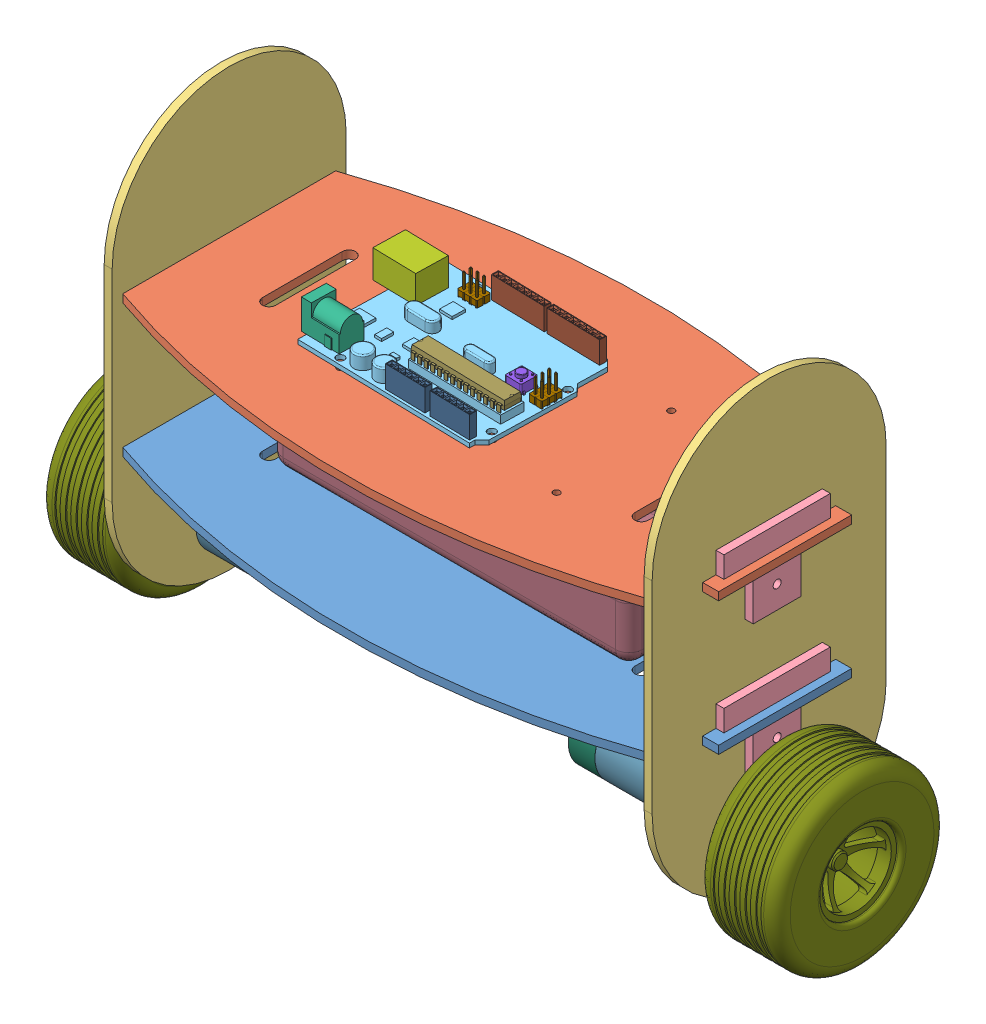
SolidWorks assembly Final Acrylic full robot, configuration Default. Lengths in mm.
Overall size (277.52 186.45 164.77).
33 component instances, 16 part files, 28 mates.
Components (placement in the parent):
- Final Acrylic body-1: Final Acrylic body [Default] at (135.5659 139.3996 253.2306) size (218 3 114.31)
- Final Acrylic body arduino-1: Final Acrylic body arduino [Default] at (135.5659 189.3996 253.2306) size (218 3 164.77)
- Acrylic side-1: Acrylic side [Default] at (235.5659 202.3996 253.2306) size (3 164 88)
- Acrylic side-2: Acrylic side [Default] at (32.5659 202.3996 253.2306) size (3 164 88)
- Acrylic T sec-1: Acrylic T sec [Default] at (241.5659 142.3996 253.2306) x (0 0 1) z (-1 0 0) size (40 28 3)
- Acrylic T sec-2: Acrylic T sec [Default] at (241.5659 192.3996 253.2306) x (0 0 1) z (-1 0 0) size (40 28 3)
- Acrylic T sec-3: Acrylic T sec [Default] at (32.5659 192.3996 253.2306) x (0 0 1) z (-1 0 0) size (40 28 3)
- Acrylic T sec-4: Acrylic T sec [Default] at (32.5659 142.3996 253.2306) x (0 0 1) z (-1 0 0) size (40 28 3)
- User Library-Arduino-UNO-1: User Library-Arduino-UNO [Predeterminado] at (128.4174 198.4807 252.7313) x (0.999721 0 0.023599) z (-0.023599 0 0.999721) size (74.65 14.9 53.3)
  - User Library-Arduino-UNO_Arduino_UNO_PCB-1: User Library-Arduino-UNO_Arduino_UNO_PCB [Predeterminado] at (-41.2845 -4.4325 26.65) size (68.65 6.6 53.3)
  - User Library-Arduino-UNO_User Library-Arduino Mega_DC POWER JACK-1: User Library-Arduino-UNO_User Library-Arduino Mega_DC POWER JACK [Default] at (-43.2845 -2.8325 18.828) x (0 0 1) z (-1 0 0) size (9.47 14.78 14.48)
  - User Library-Arduino-UNO_User Library-Arduino Mega_USB SM host-1: User Library-Arduino-UNO_User Library-Arduino Mega_USB SM host [Default] at (-39.0345 2.4175 -12.65) x (0 0 1) z (-1 0 0) size (14.86 14.22 16.5)
  - User Library-Arduino-UNO_User Library-Arduino Mega_tactile BUTTON-1: User Library-Arduino-UNO_User Library-Arduino Mega_tactile BUTTON [Default] at (15.2655 -2.8325 -1.55) x (1 0 0) z (0 1 0) size (7.9 6.2 7.35)
  - User Library-Arduino-UNO_User Library-Arduino Mega_Header Vertical 2_54mm Pitch4-1-3: User Library-Arduino-UNO_User Library-Arduino Mega_Header Vertical 2_54mm Pitch4-1 [2 Way] at (-21.2045 -2.8325 -20.11) size (2.54 9.3 5.08)
  - User Library-Arduino-UNO_User Library-Arduino Mega_Header Vertical 2_54mm Pitch4-1-4: User Library-Arduino-UNO_User Library-Arduino Mega_Header Vertical 2_54mm Pitch4-1 [2 Way] at (-23.7445 -2.8325 -20.11) size (2.54 9.3 5.08)
  - User Library-Arduino-UNO_User Library-Arduino Mega_Header Vertical 2_54mm Pitch4-1-5: User Library-Arduino-UNO_User Library-Arduino Mega_Header Vertical 2_54mm Pitch4-1 [2 Way] at (-26.2845 -2.8325 -20.11) size (2.54 9.3 5.08)
  - User Library-Arduino-UNO_User Library-Arduino Mega_Header Vertical 2_54mm Pitch4-1-6: User Library-Arduino-UNO_User Library-Arduino Mega_Header Vertical 2_54mm Pitch4-1 [2 Way] at (24.3255 -2.8325 -3.11) x (0 0 -1) z (1 0 0) size (2.54 9.3 5.08)
  - User Library-Arduino-UNO_User Library-Arduino Mega_Header Vertical 2_54mm Pitch4-1-7: User Library-Arduino-UNO_User Library-Arduino Mega_Header Vertical 2_54mm Pitch4-1 [2 Way] at (24.3255 -2.8325 1.97) x (0 0 -1) z (1 0 0) size (2.54 9.3 5.08)
  - User Library-Arduino-UNO_User Library-Arduino Mega_Header Vertical 2_54mm Pitch4-1-8: User Library-Arduino-UNO_User Library-Arduino Mega_Header Vertical 2_54mm Pitch4-1 [2 Way] at (24.3255 -2.8325 -0.57) x (0 0 -1) z (1 0 0) size (2.54 9.3 5.08)
  - User Library-Arduino-UNO_User Library-Arduino Mega_PIN HEADER FEMALE 6-1: User Library-Arduino-UNO_User Library-Arduino Mega_PIN HEADER FEMALE 6 [Default] at (-7.3445 -2.8325 24.38) size (15.24 8.3 2.54)
  - User Library-Arduino-UNO_User Library-Arduino Mega_PIN HEADER FEMALE 6-2: User Library-Arduino-UNO_User Library-Arduino Mega_PIN HEADER FEMALE 6 [Default] at (9.8955 -2.8325 24.38) size (15.24 8.3 2.54)
  - User Library-Arduino-UNO_User Library-Arduino Mega_PIN HEADER FEMALE 8-1: User Library-Arduino-UNO_User Library-Arduino Mega_PIN HEADER FEMALE 8 [Default] at (-17.5745 -2.8325 -24.38) size (20.32 8.3 2.54)
  - User Library-Arduino-UNO_User Library-Arduino Mega_PIN HEADER FEMALE 8-2: User Library-Arduino-UNO_User Library-Arduino Mega_PIN HEADER FEMALE 8 [Default] at (3.7455 -2.8325 -24.38) size (20.32 8.3 2.54)
  - User Library-Arduino-UNO_User Library-28 pin dip-1: User Library-Arduino-UNO_User Library-28 pin dip [Default] at (1.315 2.5165 10.213) x (0 0 -1) z (1 0 0) size (7.87 6.22 35.94)
- Battery-1: Battery [Default] at (69.0496 142.3996 271.4424) x (1 0 0) z (0 1 0) size (135 35 26)
- motor with encoder-1: motor with encoder [Default] at (3.1414 66.7969 276.1348) x (0 0 -1) z (1 0 0) size (25 25 74)
  - motor-1: motor [Default] at (22.9042 35.6027 32.4244) size (25 25 74)
  - encoders-1: encoders [Default] at (22.9042 35.6027 82.4244) size (25 25 10)
- motor with encoder-2: motor with encoder [Default] at (267.9903 66.7969 230.3264) x (0 0 1) z (-1 0 0) size (25 25 74)
  - motor-1: motor [Default] at (22.9042 35.6027 32.4244) size (25 25 74)
  - encoders-1: encoders [Default] at (22.9042 35.6027 82.4244) size (25 25 10)
- User Library-t01-1: User Library-t01 [Default] at (273.4947 102.3996 253.2306) x (1 0 0) z (0 0.418003 0.908445) size (30 64 64)
- User Library-t01-2: User Library-t01 [Default] at (-4.0206 102.3996 253.2306) x (-1 0 0) z (0 -0.941923 -0.335829) size (30 64 64)
Mates (geometry in assembly coordinates):
- Coincident2: coincident anti-aligned: plane of Final Acrylic body arduino-1 through (235.5659 192.3996 228.2306) normal (0 0 -1); plane of Acrylic side-1 through (238.5659 192.3996 228.2306) normal (0 0 1)
- Coincident3: coincident anti-aligned: plane of Final Acrylic body arduino-1 through (135.5659 192.3996 10.3879) normal (0 1 0); plane of Acrylic side-1 through (238.5659 192.3996 278.2306) normal (0 -1 0)
- Coincident4: coincident anti-aligned: plane of Final Acrylic body arduino-1 through (235.5659 192.3996 293.2306) normal (1 0 0); plane of Acrylic side-1 through (235.5659 202.3996 253.2306) normal (-1 0 0)
- Coincident5: coincident anti-aligned: plane of Final Acrylic body-1 through (235.5659 142.3996 278.2306) normal (0 0 1); plane of Acrylic side-1 through (238.5659 142.3996 278.2306) normal (0 0 -1)
- Coincident6: coincident anti-aligned: plane of Final Acrylic body-1 through (135.5659 139.3996 10.3879) normal (0 -1 0); plane of Acrylic side-1 through (238.5659 139.3996 228.2306) normal (0 1 0)
- Coincident7: coincident anti-aligned: plane of Final Acrylic body-1 through (235.5659 142.3996 293.2306) normal (1 0 0); plane of Acrylic side-1 through (235.5659 202.3996 253.2306) normal (-1 0 0)
- Coincident8: coincident anti-aligned: plane of Acrylic side-1 through (238.5659 202.3996 253.2306) normal (1 0 0); plane of Acrylic T sec-2 through (238.5659 192.3996 253.2306) normal (-1 0 0)
- Coincident9: coincident anti-aligned: plane of Acrylic side-1 through (238.5659 202.3996 253.2306) normal (1 0 0); plane of Acrylic T sec-1 through (238.5659 142.3996 253.2306) normal (-1 0 0)
- Concentric1: concentric anti-aligned: circle of Acrylic side-1; circle of Acrylic T sec-1
- Concentric2: concentric anti-aligned: circle of Acrylic side-1; circle of Acrylic T sec-2
- Coincident11: coincident anti-aligned: plane of Final Acrylic body-1 through (135.5659 139.3996 10.3879) normal (0 -1 0); plane of Acrylic side-2 through (35.5659 139.3996 228.2306) normal (0 1 0)
- Coincident12: coincident anti-aligned: plane of Final Acrylic body arduino-1 through (135.5659 192.3996 10.3879) normal (0 1 0); plane of Acrylic side-2 through (35.5659 192.3996 278.2306) normal (0 -1 0)
- Coincident13: coincident anti-aligned: plane of Final Acrylic body arduino-1 through (35.5659 192.3996 278.2306) normal (0 0 1); plane of Acrylic side-2 through (35.5659 192.3996 278.2306) normal (0 0 -1)
- Coincident14: coincident anti-aligned: plane of Final Acrylic body arduino-1 through (35.5659 192.3996 293.2306) normal (-1 0 0); plane of Acrylic side-2 through (35.5659 202.3996 253.2306) normal (1 0 0)
- Coincident15: coincident anti-aligned: plane of Acrylic side-2 through (32.5659 202.3996 253.2306) normal (-1 0 0); plane of Acrylic T sec-3 through (32.5659 192.3996 253.2306) normal (1 0 0)
- Coincident16: coincident anti-aligned: plane of Acrylic side-2 through (32.5659 202.3996 253.2306) normal (-1 0 0); plane of Acrylic T sec-4 through (32.5659 142.3996 253.2306) normal (1 0 0)
- Concentric3: concentric aligned: cylinder of Acrylic side-2 through (35.5659 130.8996 253.2306) axis (-1 0 0) radius 1.5; circle of Acrylic T sec-4
- Concentric4: concentric anti-aligned: circle of Acrylic side-2; circle of Acrylic T sec-3
- Concentric8: concentric aligned: circle of Final Acrylic body arduino-1; circle of User Library-Arduino-UNO-1/User Library-Arduino-UNO_Arduino_UNO_PCB-1
- Coincident18: coincident anti-aligned: plane of Final Acrylic body-1 through (135.5659 142.3996 10.3879) normal (0 1 0); plane of Battery-1 through (69.0496 142.3996 271.4424) normal (0 -1 0)
- Concentric9: concentric anti-aligned: cylinder of Acrylic side-1 through (238.5659 102.3996 261.7306) axis (-1 0 0) radius 1.5; cylinder of motor with encoder-2/motor-1 through (230.5659 102.3996 261.7306) axis (1 0 0) radius 1.5
- Concentric10: concentric aligned: circle of Acrylic side-1; circle of motor with encoder-2/motor-1
- Coincident19: coincident aligned: plane of Acrylic side-1 through (235.5659 202.3996 253.2306) normal (-1 0 0); circle of motor with encoder-2/motor-1
- Concentric11: concentric anti-aligned: circle of Acrylic side-2; circle of motor with encoder-1/motor-1
- Concentric12: concentric aligned: cylinder of Acrylic side-2 through (35.5659 102.3996 261.7306) axis (-1 0 0) radius 1.5; circle of motor with encoder-1/motor-1
- Coincident21: coincident anti-aligned: plane of Acrylic side-2 through (35.5659 202.3996 253.2306) normal (1 0 0); plane of motor with encoder-1/motor-1 through (35.5659 102.3996 253.2306) normal (-1 0 0)
- Concentric13: concentric aligned: circle of motor with encoder-1/motor-1; cylinder of User Library-t01-2 through (3.9794 102.3996 253.2306) axis (-1 0 0) radius 3
- Concentric14: concentric anti-aligned: cylinder of motor with encoder-2/motor-1 through (248.5659 102.3996 253.2306) axis (-1 0 0) radius 2; cylinder of User Library-t01-1 through (265.4947 102.3996 253.2306) axis (1 0 0) radius 3
